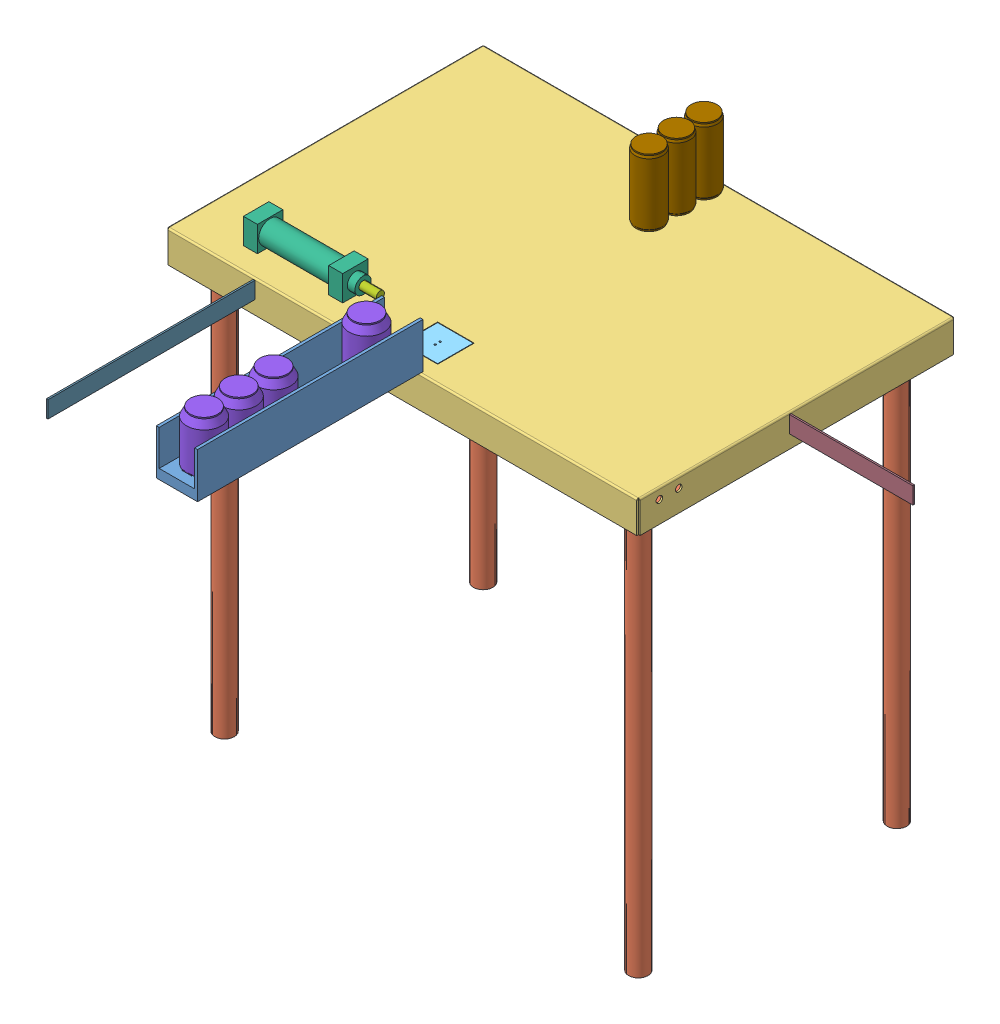
SolidWorks assembly Full_Assembly_v9, configuration Default. Lengths in mm.
Overall size (1169.6 1032.54 1072.2).
21 component instances, 14 part files, 68 mates.
Components (placement in the parent):
- Goose Output-1: Goose Output [Default] at (293.9688 417.0931 1038.3317) size (80.96 88.9 442.73)
- M37_Metal_Table_v2-1: M37_Metal_Table_v2 [Default] at (-122.75 348.1575 1031.9817) size (914.4 863.6 609.6)
- Table Topper-1: Table Topper [Default] at (-125.925 348.1575 1035.1567) size (927.1 62.58 622.3)
- Load Cell Assembly-1: Load Cell Assembly [Default] at (309.0555 355.8164 890.1864) size (69.85 23.2 103.99)
  - Load Cell and Brace-1: Load Cell and Brace [Default] at (-9.1055 31.7162 92.7424) size (69 14.2 83)
  - scalePlate_v2_234-1: scalePlate_v2_234 [Default] at (-9.5305 54.9162 113.7283) x (0 0 -1) z (-1 0 0) size (69.85 9 69.85)
- Cylinder-1: Cylinder [Default] at (-22.0508 460.7325 943.9897) x (0 0 1) z (1 0 0) size (50 50 210)
- Rod-1: Rod [Default] at (221.9492 435.7325 968.9897) x (0 0.637822 -0.770184) z (0 0.770184 0.637822) size (16 134 16)
- can355mL-1: can355mL [Default] at (334.45 410.7325 1291.3582) x (0 0 -1) z (1 0 0) size (68.26 122.24 68.26)
- can355mL-2: can355mL [Default] at (334.45 410.7325 1427.8832) x (0 0 -1) z (1 0 0) size (68.26 122.24 68.26)
- can355mL-3: can355mL [Default] at (334.45 410.7325 1359.6207) x (0 0 -1) z (1 0 0) size (68.26 122.24 68.26)
- can250mL-1: can250mL [Default] at (334.45 410.7325 553.8493) x (-0.934308 0 -0.356465) z (0.356465 0 -0.934308) size (53.98 131.76 53.98)
- can250mL-2: can250mL [Default] at (334.45 410.7325 499.8743) x (0.439436 0 -0.898274) z (0.898274 0 0.439436) size (53.98 131.76 53.98)
- can250mL-3: can250mL [Default] at (334.45 410.7325 445.8993) x (0.515444 0 0.856923) z (-0.856923 0 0.515444) size (53.98 131.76 53.98)
- can355mL-7: can355mL [Default] at (334.45 410.7325 1108.8451) x (0 0 -1) z (1 0 0) size (68.26 122.24 68.26)
- AmpCase_Assembly_v1-1: AmpCase_Assembly_v1 [Default] at (378.0256 448.8533 898.6464) x (0 0 -1) z (-1 0 0) size (83 33 59)
  - AmpCase_LID_83x59x33_v1-1: AmpCase_LID_83x59x33_v1 [Default] at (42.2994 74.2958 -6.3457) x (1 0 0) z (0 0 -1) size (83 7 59)
  - AmpCase83x59x33_v1-1: AmpCase83x59x33_v1 [Default] at (42.2994 41.2958 52.6543) size (83 26 59)
- Solenoid_v1-1: Solenoid_v1 [Default] at (452.5858 385.5575 857.7853) size (118 22 83)
- Slats_Long_v1-1: Slats_Long_v1 [Default] at (119.7476 374.5575 738.5181) size (920.75 33 3.17)
- Slats_Short_v1-1: Slats_Short_v1 [Default] at (44.7928 374.5575 828.583) x (0 0 1) z (-1 0 0) size (615.95 33 3.17)
Mates (geometry in assembly coordinates):
- Width1: width aligned: plane of M37_Metal_Table_v2-1 through (791.65 373.5575 1031.9817) normal (1 0 0); plane of M37_Metal_Table_v2-1 through (-122.75 373.5575 1031.9817) normal (-1 0 0); plane of Table Topper-1 through (798 407.5575 1035.1567) normal (1 0 0); plane of Table Topper-1 through (-129.1 407.5575 1035.1567) normal (-1 0 0)
- Width2: width aligned: plane of M37_Metal_Table_v2-1 through (-122.75 373.5575 1031.9817) normal (0 0 1); plane of M37_Metal_Table_v2-1 through (-122.75 373.5575 422.3817) normal (0 0 -1); plane of Table Topper-1 through (-125.925 407.5575 1038.3317) normal (0 0 1); plane of Table Topper-1 through (-125.925 407.5575 416.0317) normal (0 0 -1)
- Distance1: distance = 863.6 mm aligned: plane of M37 Metal Table-1 through (-122.75 -446.5069 1031.9817) normal (0 -1 0); plane of Goose Output-1 through (374.9313 417.0931 1481.0664) normal (0 -1 0)
- LimitDistance1: limit distance = 423.0687 mm aligned: plane of Goose Output-1 through (374.9313 505.9931 1481.0664) normal (1 0 0); plane of Table Topper-1 through (798 407.5575 1035.1567) normal (1 0 0)
- LimitDistance2: limit distance = 423.0687 mm aligned: plane of Table Topper-1 through (-129.1 407.5575 1035.1567) normal (-1 0 0); plane of Goose Output-1 through (293.9688 417.0931 1481.0664) normal (-1 0 0)
- Parallel1: parallel aligned: plane of Goose Output-1 through (299.525 436.1431 1481.0664) normal (0 1 0); plane of Table Topper-1 through (-125.925 410.7325 1035.1567) normal (0 1 0)
- Coincident7: coincident aligned: plane of Table Topper-1 through (-125.925 410.7325 1035.1567) normal (0 1 0); plane of Load Cell Assembly-1/scalePlate_v2_234-1 through (299.525 410.7325 1003.9147) normal (0 1 0)
- Concentric1: concentric anti-aligned: cylinder of Cylinder-1 through (187.9492 435.7325 968.9897) axis (-1 0 0) radius 16; cylinder of Rod-1 through (87.9492 435.7325 968.9897) axis (1 0 0) radius 8
- LimitDistance3: limit distance = 34 mm aligned: plane of Rod-1 through (221.9492 435.7325 968.9897) normal (1 0 0); plane of Cylinder-1 through (187.9492 435.7325 968.9897) normal (1 0 0)
- Parallel2: parallel anti-aligned: plane of Table Topper-1 through (-125.925 407.5575 1038.3317) normal (0 0 1); plane of Cylinder-1 through (172.9492 460.7325 943.9897) normal (0 0 -1)
- Coincident9: coincident anti-aligned: plane of Table Topper-1 through (-125.925 410.7325 1035.1567) normal (0 1 0); plane of Cylinder-1 through (5.4492 410.7325 943.9897) normal (0 -1 0)
- Width3: width anti-aligned: plane of Goose Output-1 through (374.9313 505.9931 1481.0664) normal (1 0 0); plane of Goose Output-1 through (293.9688 417.0931 1481.0664) normal (-1 0 0); plane of Load Cell Assembly-1/scalePlate_v2_234-1 through (299.525 406.7325 1003.9147) normal (-1 0 0); plane of Load Cell Assembly-1/scalePlate_v2_234-1 through (369.375 406.7325 1003.9147) normal (1 0 0)
- Width4: width anti-aligned: plane of Cylinder-1 through (172.9492 460.7325 943.9897) normal (0 0 -1); plane of Cylinder-1 through (172.9492 460.7325 993.9897) normal (0 0 1); plane of Load Cell Assembly-1/scalePlate_v2_234-1 through (299.525 406.7325 1003.9147) normal (0 0 1); plane of Load Cell Assembly-1/scalePlate_v2_234-1 through (299.525 406.7325 934.0647) normal (0 0 -1)
- Width5: width anti-aligned: plane of Table Topper-1 through (798 407.5575 1035.1567) normal (1 0 0); plane of Table Topper-1 through (-129.1 407.5575 1035.1567) normal (-1 0 0); plane of Load Cell Assembly-1/scalePlate_v2_234-1 through (299.525 406.7325 1003.9147) normal (-1 0 0); plane of Load Cell Assembly-1/scalePlate_v2_234-1 through (369.375 406.7325 1003.9147) normal (1 0 0)
- Coincident11: coincident anti-aligned: plane of Table Topper-1 through (-125.925 410.7325 1035.1567) normal (0 1 0); plane of can250mL-1 through (310.7186 410.7325 544.7951) normal (0 -1 0)
- Coincident18: coincident anti-aligned: plane of Table Topper-1 through (-125.925 410.7325 1035.1567) normal (0 1 0); plane of can355mL-2 through (334.45 410.7325 1400.8957) normal (0 -1 0)
- Coincident19: coincident anti-aligned: plane of Table Topper-1 through (-125.925 410.7325 1035.1567) normal (0 1 0); plane of can355mL-3 through (334.45 410.7325 1332.6332) normal (0 -1 0)
- Tangent5: tangent anti-aligned: cylinder of can355mL-2 through (334.45 410.7325 1427.8832) axis (0 -1 0) radius 34.1313; cylinder of can355mL-3 through (334.45 410.7325 1359.6207) axis (0 -1 0) radius 34.1313
- Width6: width: plane of Goose Output-1 through (299.525 505.9931 1481.0664) normal (1 0 0); plane of Goose Output-1 through (369.375 436.1431 1481.0664) normal (-1 0 0); cylinder of can250mL-1 through (334.45 410.7325 553.8493) axis (0 -1 0) radius 26.9875
- Width8: width: plane of Goose Output-1 through (369.375 436.1431 1481.0664) normal (-1 0 0); plane of Goose Output-1 through (299.525 505.9931 1481.0664) normal (1 0 0); cylinder of can355mL-2 through (334.45 410.7325 1427.8832) axis (0 -1 0) radius 34.1313
- Width10: width: plane of Goose Output-1 through (299.525 505.9931 1481.0664) normal (1 0 0); plane of Goose Output-1 through (369.375 436.1431 1481.0664) normal (-1 0 0); cylinder of can355mL-3 through (334.45 410.7325 1359.6207) axis (0 -1 0) radius 34.1313
- Coincident20: coincident anti-aligned: plane of Table Topper-1 through (-125.925 410.7325 1035.1567) normal (0 1 0); plane of can250mL-2 through (345.6117 410.7325 477.0581) normal (0 -1 0)
- Coincident21: coincident anti-aligned: plane of Table Topper-1 through (-125.925 410.7325 1035.1567) normal (0 1 0); plane of can250mL-3 through (347.5423 410.7325 467.6651) normal (0 -1 0)
- Tangent6: tangent anti-aligned: cylinder of can250mL-1 through (334.45 410.7325 553.8493) axis (0 -1 0) radius 26.9875; cylinder of can250mL-2 through (334.45 410.7325 499.8743) axis (0 -1 0) radius 26.9875
- Tangent7: tangent anti-aligned: cylinder of can250mL-2 through (334.45 410.7325 499.8743) axis (0 -1 0) radius 26.9875; cylinder of can250mL-3 through (334.45 410.7325 445.8993) axis (0 -1 0) radius 26.9875
- Width11: width: plane of Goose Output-1 through (299.525 505.9931 1481.0664) normal (1 0 0); plane of Goose Output-1 through (369.375 436.1431 1481.0664) normal (-1 0 0); cylinder of can250mL-2 through (334.45 410.7325 499.8743) axis (0 -1 0) radius 26.9875
- Width12: width: plane of Goose Output-1 through (299.525 505.9931 1481.0664) normal (1 0 0); plane of Goose Output-1 through (369.375 436.1431 1481.0664) normal (-1 0 0); cylinder of can250mL-3 through (334.45 410.7325 445.8993) axis (0 -1 0) radius 26.9875
- Coincident22: coincident anti-aligned: plane of Goose Output-1 through (293.9688 417.0931 1038.3317) normal (0 0 -1); plane of Table Topper-1 through (-125.925 407.5575 1038.3317) normal (0 0 1)
- Width14: width aligned: plane of Table Topper-1 through (370.391 348.1575 1004.9307) normal (-1 0 0); plane of Load Cell Assembly-1/scalePlate_v2_234-1 through (298.509 348.1575 1004.9307) normal (1 0 0); plane of Table Topper-1 through (299.525 406.7325 1003.9147) normal (-1 0 0); plane of Load Cell Assembly-1/scalePlate_v2_234-1 through (369.375 406.7325 1003.9147) normal (1 0 0)
- Width15: width anti-aligned: plane of Table Topper-1 through (298.509 348.1575 1004.9307) normal (0 0 -1); plane of Load Cell Assembly-1/scalePlate_v2_234-1 through (298.509 348.1575 933.0487) normal (0 0 1); plane of Table Topper-1 through (299.525 406.7325 1003.9147) normal (0 0 1); plane of Load Cell Assembly-1/scalePlate_v2_234-1 through (299.525 406.7325 934.0647) normal (0 0 -1)
- Width17: width: plane of Goose Output-1 through (369.375 436.1431 1481.0664) normal (-1 0 0); plane of can355mL-4 through (299.525 505.9931 1481.0664) normal (1 0 0); cylinder of Goose Output-1 through (334.45 436.1431 1259.8293) axis (0 -1 0) radius 34.1313
- Coincident31: coincident anti-aligned: plane of Table Topper-1 through (-125.925 410.7325 1035.1567) normal (0 1 0); plane of can355mL-7 through (334.45 410.7325 1081.8576) normal (0 -1 0)
- Width19: width: plane of Goose Output-1 through (369.375 436.1431 1481.0664) normal (-1 0 0); plane of can355mL-7 through (299.525 505.9931 1481.0664) normal (1 0 0); cylinder of Goose Output-1 through (334.45 410.7325 1108.8451) axis (0 -1 0) radius 34.1313
- Coincident33: coincident anti-aligned: plane of Table Topper-1 through (-125.925 410.7325 1035.1567) normal (0 1 0); plane of can355mL-1 through (334.45 410.7325 1264.3707) normal (0 -1 0)
- Tangent13: tangent anti-aligned: cylinder of can355mL-1 through (334.45 410.7325 1291.3582) axis (0 -1 0) radius 34.1313; cylinder of can355mL-3 through (334.45 410.7325 1359.6207) axis (0 -1 0) radius 34.1313
- Width20: width: plane of Goose Output-1 through (299.525 505.9931 1481.0664) normal (1 0 0); plane of can355mL-1 through (369.375 436.1431 1481.0664) normal (-1 0 0); cylinder of Goose Output-1 through (334.45 410.7325 1291.3582) axis (0 -1 0) radius 34.1313
- Parallel4: parallel aligned: plane of M37_Metal_Table_v2-1 through (-122.75 373.5575 1031.9817) normal (0 0 1); plane of can355mL-7 through (334.45 410.7325 1142.9764) normal (0 0 1)
- Parallel5: parallel aligned: plane of M37_Metal_Table_v2-1 through (-122.75 373.5575 1031.9817) normal (0 0 1); plane of can355mL-2 through (334.45 410.7325 1462.0144) normal (0 0 1)
- Parallel6: parallel aligned: plane of M37_Metal_Table_v2-1 through (-122.75 373.5575 1031.9817) normal (0 0 1); plane of can355mL-3 through (334.45 410.7325 1393.7519) normal (0 0 1)
- Parallel7: parallel aligned: plane of M37_Metal_Table_v2-1 through (-122.75 373.5575 1031.9817) normal (0 0 1); plane of can355mL-1 through (334.45 410.7325 1325.4894) normal (0 0 1)
- LimitDistance14: limit distance = 182.5131 mm aligned: plane of can355mL-7 through (334.45 410.7325 1142.9764) normal (0 0 1); plane of can355mL-1 through (334.45 410.7325 1325.4894) normal (0 0 1)
- Tangent14: tangent anti-aligned: cylinder of can355mL-9 through (334.45 412.9931 1319.9352) axis (0 -1 0) radius 34.1313; cylinder of can355mL-10 through (334.45 412.9931 1388.1977) axis (0 -1 0) radius 34.1313
- Tangent15: tangent anti-aligned: cylinder of can355mL-8 through (334.45 412.9931 1456.4602) axis (0 -1 0) radius 34.1313; cylinder of can355mL-10 through (334.45 412.9931 1388.1977) axis (0 -1 0) radius 34.1313
- Coincident38: coincident anti-aligned: plane of Table Topper-1 through (-125.925 410.7325 1035.1567) normal (0 1 0); plane of can355mL-8 through (334.45 412.9931 1429.4727) normal (0 -1 0)
- Coincident39: coincident aligned: plane of can355mL-9 through (334.45 412.9931 1292.9477) normal (0 -1 0); plane of can355mL-10 through (334.45 412.9931 1361.2102) normal (0 -1 0)
- Coincident40: coincident anti-aligned: plane of Table Topper-1 through (-125.925 410.7325 1035.1567) normal (0 1 0); plane of can355mL-10 through (334.45 412.9931 1361.2102) normal (0 -1 0)
- Width21: width: plane of Goose Output-1 through (299.525 505.9931 1481.0664) normal (1 0 0); plane of Goose Output-1 through (369.375 436.1431 1481.0664) normal (-1 0 0); cylinder of can355mL-8 through (334.45 412.9931 1456.4602) axis (0 -1 0) radius 34.1313
- Width22: width: plane of Goose Output-1 through (374.9313 505.9931 1481.0664) normal (1 0 0); plane of Goose Output-1 through (293.9688 417.0931 1481.0664) normal (-1 0 0); cylinder of can355mL-10 through (334.45 412.9931 1388.1977) axis (0 -1 0) radius 34.1313
- Width23: width: plane of Goose Output-1 through (374.9313 505.9931 1481.0664) normal (1 0 0); plane of Goose Output-1 through (293.9688 417.0931 1481.0664) normal (-1 0 0); cylinder of can355mL-9 through (334.45 412.9931 1319.9352) axis (0 -1 0) radius 34.1313
- LimitDistance15: limit distance = 98.6078 mm aligned: plane of can355mL-9 through (334.45 412.9931 1354.0664) normal (0 0 1); plane of can355mL-2 through (334.45 410.7325 1462.0144) normal (0 0 1)
- Parallel8: parallel aligned: plane of M37_Metal_Table_v2-1 through (-122.75 373.5575 1031.9817) normal (0 0 1); plane of can355mL-8 through (334.45 412.9931 1490.5914) normal (0 0 1)
- Parallel10: parallel aligned: plane of M37_Metal_Table_v2-1 through (-122.75 373.5575 1031.9817) normal (0 0 1); plane of can355mL-10 through (334.45 412.9931 1422.3289) normal (0 0 1)
- LimitDistance16: limit distance = 0 mm aligned: plane of can355mL-8 through (334.45 412.9931 1490.5914) normal (0 0 1); plane of Goose Output-1 through (293.9688 417.0931 1481.0664) normal (0 0 1)
- Parallel12: parallel aligned: plane of M37_Metal_Table_v2-1 through (-122.75 373.5575 1031.9817) normal (0 0 1); plane of can355mL-11 through (334.45 412.9931 1012.7539) normal (0 0 1)
- LimitDistance18: limit distance = 68.2625 mm aligned: plane of can355mL-11 through (334.45 412.9931 1012.7539) normal (0 0 1); plane of can355mL-7 through (334.45 410.7325 1142.9764) normal (0 0 1)
- PathMate3: path: point of can355mL-11
- Parallel13: parallel anti-aligned: plane of Table Topper-1 through (-125.925 410.7325 1035.1567) normal (0 1 0); plane of can355mL-11 through (334.45 412.9931 951.6352) normal (0 -1 0)
- Parallel14: parallel aligned: plane of M37_Metal_Table_v2-1 through (-122.75 373.5575 1031.9817) normal (0 0 1); plane of can355mL-11 through (334.45 412.9931 1012.7539) normal (0 0 1)
- Coincident41: coincident aligned: plane of M37_Metal_Table_v2-1 through (-122.75 348.1575 1031.9817) normal (0 -1 0); plane of Table Topper-1 through (-125.925 348.1575 1035.1567) normal (0 -1 0)
- Coincident42: coincident anti-aligned: plane of Table Topper-1 through (-125.925 407.5575 1035.1567) normal (0 -1 0); plane of AmpCase_Assembly_v1-1/AmpCase83x59x33_v1-1 through (325.3712 407.5575 856.347) normal (0 1 0)
- Parallel15: parallel aligned: plane of M37_Metal_Table_v2-1 through (-122.75 373.5575 1031.9817) normal (0 0 1); plane of AmpCase_Assembly_v1-1/AmpCase83x59x33_v1-1 through (325.3712 404.5575 856.347) normal (0 0 1)
- Parallel16: parallel aligned: plane of M37_Metal_Table_v2-1 through (-122.75 373.5575 1031.9817) normal (0 0 1); plane of Solenoid_v1-1 through (452.5858 407.5575 857.7853) normal (0 0 1)
- Coincident45: coincident aligned: plane of AmpCase_Assembly_v1-1/AmpCase83x59x33_v1-1 through (325.3712 407.5575 856.347) normal (0 1 0); plane of Solenoid_v1-1 through (452.5858 407.5575 857.7853) normal (0 1 0)
- Coincident46: coincident aligned: plane of M37_Metal_Table_v2-1 through (-122.75 348.1575 1031.9817) normal (0 -1 0); plane of M37 Metal Table-2 through (-136.9971 348.1681 1554.8123) normal (0 -1 0)
- Parallel17: parallel aligned: plane of M37_Metal_Table_v2-1 through (-122.75 373.5575 1031.9817) normal (0 0 1); plane of Slats_Long_v1-1 through (119.7476 374.5575 741.6931) normal (0 0 1)
- Parallel18: parallel anti-aligned: plane of M37_Metal_Table_v2-1 through (791.65 373.5575 1031.9817) normal (1 0 0); plane of Slats_Short_v1-1 through (41.6178 374.5575 828.583) normal (-1 0 0)
- Coincident48: coincident aligned: plane of AmpCase_Assembly_v1-1/AmpCase83x59x33_v1-1 through (325.3712 407.5575 856.347) normal (0 1 0); plane of Slats_Long_v1-1 through (119.7476 407.5575 741.6931) normal (0 1 0)
- Coincident49: coincident aligned: plane of AmpCase_Assembly_v1-1/AmpCase83x59x33_v1-1 through (325.3712 407.5575 856.347) normal (0 1 0); plane of Slats_Short_v1-1 through (41.6178 407.5575 828.583) normal (0 1 0)
